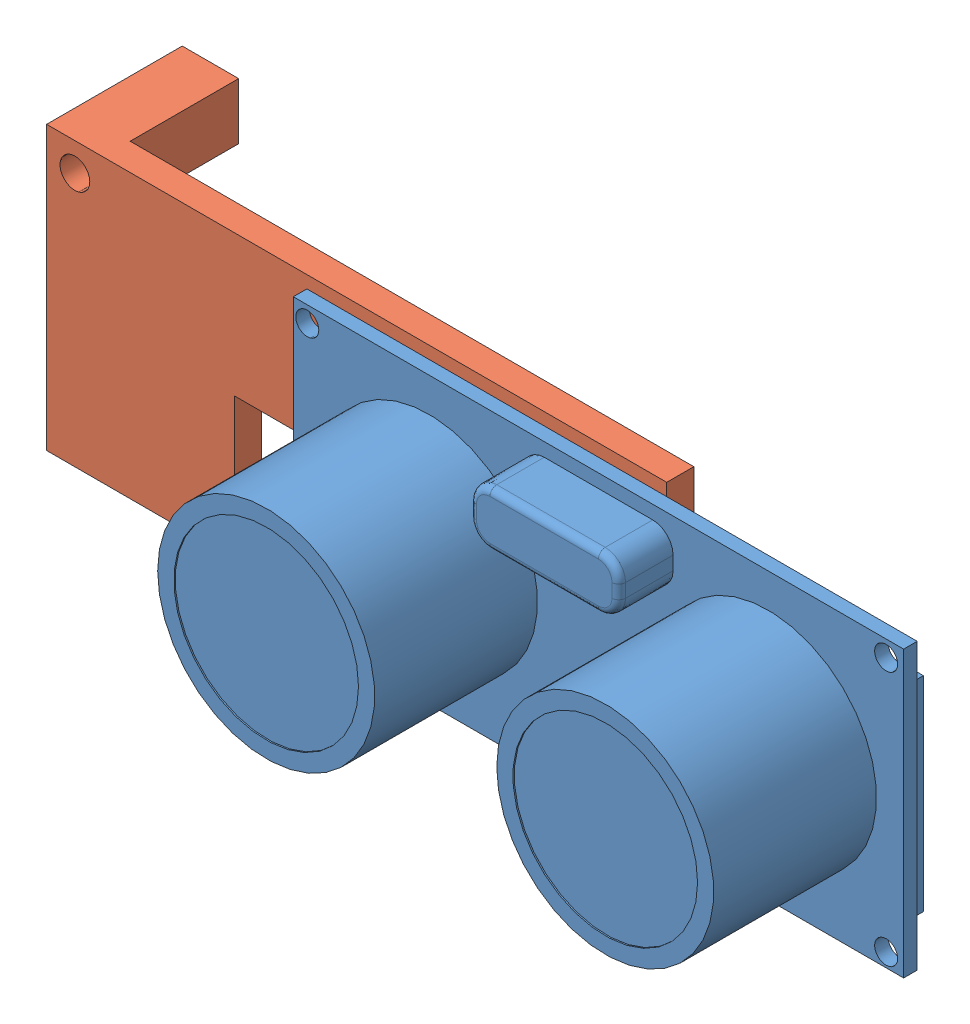
SolidWorks assembly Baugruppe3, configuration Standard. Lengths in mm.
Overall size (65.19 21 24).
2 component instances, 2 part files, 1 mates.
Components (placement in the parent):
- LtraschallSens-1: LtraschallSens [Default] at (9.1739 2.3877 -5.5) size (45 21 15)
- Teil4-1: Teil4 [Default] at (-10.6539 2.3885 -8.5) size (45.72 20.83 10)
Mates (geometry in assembly coordinates):
- Deckungsgleich3: coincident anti-aligned: plane of LtraschallSens-1 through (9.1739 2.3877 -6.5) normal (0 0 -1); plane of Teil4-1 through (-10.6539 2.3885 -6.5) normal (0 0 1)
